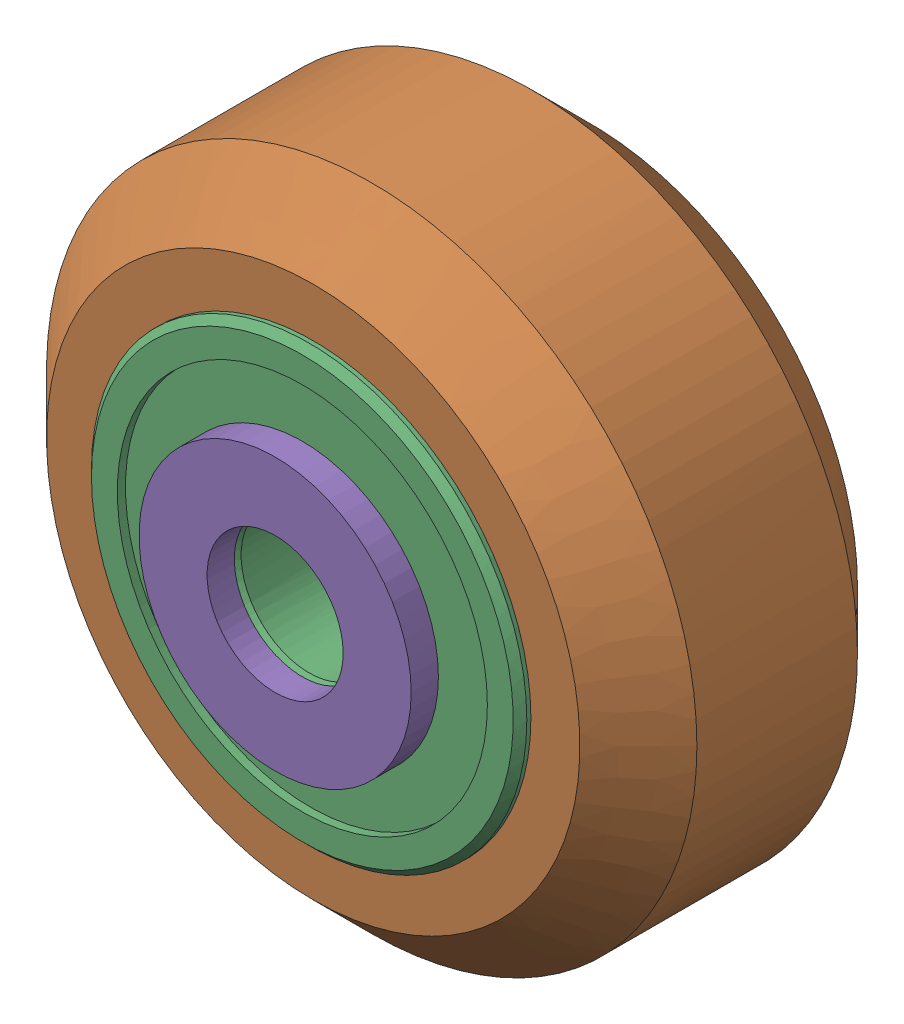
SolidWorks assembly Xtreme Solid V Wheel Kit Assembly_2, configuration Default. Lengths in mm.
Overall size (23.9 23.9 13).
6 component instances, 3 part files, 0 mates.
Components (placement in the parent):
- Precision Shim - 10x5x1mm-1: Precision Shim - 10x5x1mm [Default] at origin size (10 10 1)
- Xtreme Solid V Wheel Assembly_2-1: Xtreme Solid V Wheel Assembly_2 [Default] at (154.85 55 -23.5) size (23.9 23.9 11)
  - Xtreme Solid V Wheel-1: Xtreme Solid V Wheel [Default] at (-154.85 -55 30) x (0 0 1) z (-1 0 0) size (10.2 23.9 23.9)
  - Wheel+Kit+-+5x16x5mm+Sealed+Radial+Ball+Bearing.step.f3d-1: Wheel+Kit+-+5x16x5mm+Sealed+Radial+Ball+Bearing.step.f3d [Default] at (-154.85 -55 30) x (0 1 0) z (-1 0 0) size (16 5 16)
  - Wheel+Kit+-+5x16x5mm+Sealed+Radial+Ball+Bearing.step.f3d-2: Wheel+Kit+-+5x16x5mm+Sealed+Radial+Ball+Bearing.step.f3d [Default] at (-154.85 -55 30) x (0 1 0) z (1 0 0) size (16 5 16)
- Precision Shim - 10x5x1mm-2: Precision Shim - 10x5x1mm [Default] at (0 0 12) size (10 10 1)
